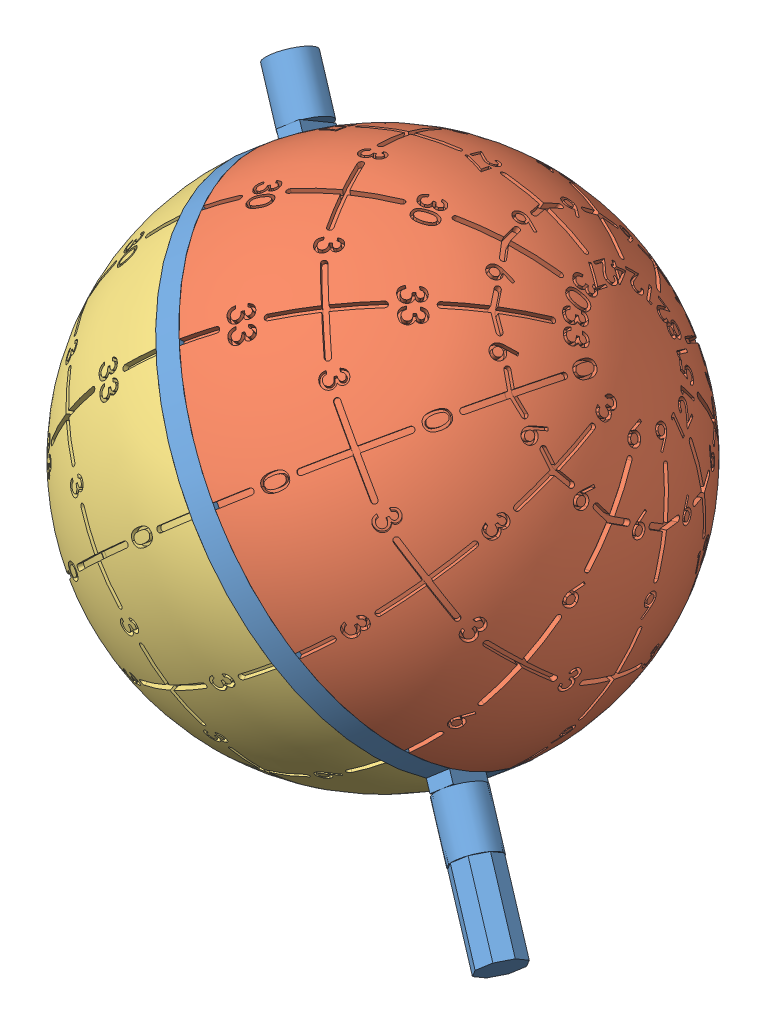
SolidWorks assembly plate, configuration Default. Lengths in mm.
Overall size (138.24 147.99 129.73).
8 component instances, 8 part files, 16 mates.
Components (placement in the parent):
- BallPlate-1: BallPlate [Default] x (0.678648 -0.634798 0.369415) z (0.007266 0.508751 0.860883) size (127.54 8 88.9)
- Ball_V9_final_Top-1: Ball_V9_final_Top [Default] x (0.658953 -0.734427 0.162472) z (0.162472 0.349875 0.9226) size (88.8 42.45 88.81)
- Ball_V9_final_Bot-1: Ball_V9_final_Bot [Default] x (0.658953 -0.734427 0.162472) z (0.162472 0.349875 0.9226) size (88.8 87.56 88.81)
- SKF 625-1: SKF 625 [Default] at (-1.8361 -1.4539 0.8747) x (0.734427 0.581553 -0.349875) z (0.162472 0.349875 0.9226) size (5 16 16)
- Servo-2: Servo [noHorn] at (1.3234 -9.0246 -17.9389) x (-0.007266 -0.508751 -0.860883) z (0.678648 -0.634798 0.369415) size (19.8 47.23 67)
- BallShaft-1: BallShaft [Default] at (1.6489 1.3057 -0.7855) x (-0.141735 -0.372726 -0.917053) z (0.663722 -0.723099 0.191314) size (13.5 16.75 13.5)
- YawServoGear-1: YawServoGear [Default] at (7.1858 7.691 -27.8667) x (0.658953 -0.734427 0.162472) z (-0.734427 -0.581553 0.349875) size (24.43 24.43 3)
- BallGear2-2: BallGear2 [Default] at (14.3213 11.3403 -6.8226) x (0.294586 0.191268 0.936288) z (-0.734427 -0.581553 0.349875) size (24.43 24.43 3)
Mates (geometry in assembly coordinates):
- Concentric1: concentric: circle of Ball_V9_final_Top-1; circle of BallPlate-1
- Coincident1: coincident: plane of BallPlate-1 through (1.4689 1.1631 -0.6998) normal (0.734427 0.581553 -0.349875); plane of Ball_V9_final_Top-1 through (1.4689 1.1631 -0.6998) normal (-0.734427 -0.581553 0.349875)
- Concentric2: concentric: circle of Ball_V9_final_Bot-1; circle of BallPlate-1
- Coincident2: coincident: plane of BallPlate-1 through (-1.4689 -1.1631 0.6998) normal (-0.734427 -0.581553 0.349875); plane of Ball_V9_final_Bot-1 through (-1.4689 -1.1631 0.6998) normal (0.734427 0.581553 -0.349875)
- Concentric3: concentric: circle of BallPlate-1; circle of SKF 625-1
- Coincident4: coincident: plane of BallPlate-1 through (1.8361 1.4539 -0.8747) normal (0.734427 0.581553 -0.349875); plane of SKF 625-1 through (-2.546 6.3378 -1.9551) normal (0.734427 0.581553 -0.349875)
- Tangent1: tangent: cylinder of BallPlate-1 through (1.8361 1.4539 -0.8747) axis (-0.734427 -0.581553 0.349875) radius 10.125; plane of Servo-2 through (-12.3813 8.8984 -16.9153) normal (0.007266 0.508751 0.860883)
- Coincident5: coincident: plane of BallPlate-1 through (1.4689 1.1631 -0.6998) normal (0.734427 0.581553 -0.349875); plane of Servo-2 through (1.3234 -9.0246 -17.9389) normal (-0.734427 -0.581553 0.349875)
- Parallel1: parallel: line of BallPlate-1 through (32.963 -30.3583 13.016) axis (-0.678648 0.634798 -0.369415); line of Servo-2 through (20.592 -21.3697 -22.3059) axis (-0.678648 0.634798 -0.369415)
- Lock4: lock: unknown of BallPlate-1; unknown of Servo-2
- Coincident6: coincident: plane of Servo-2 through (7.1858 7.691 -27.8667) normal (0.734427 0.581553 -0.349875); plane of YawServoGear-1 through (7.1858 7.691 -27.8667) normal (0.734427 0.581553 -0.349875)
- Concentric5: concentric: circle of Servo-2; circle of YawServoGear-1
- Coincident8: coincident: plane of YawServoGear-1 through (7.1858 7.691 -27.8667) normal (0.734427 0.581553 -0.349875); plane of BallGear2-2 through (14.3213 11.3403 -6.8226) normal (0.734427 0.581553 -0.349875)
- Coincident12: coincident: plane of BallShaft-1 through (14.4143 7.9102 -3.7542) normal (0.734427 0.581553 -0.349875); plane of BallGear2-2 through (12.1181 9.5956 -5.7729) normal (-0.734427 -0.581553 0.349875)
- Parallel3: parallel: plane of SKF 625-1 through (-0.009 3.5103 -1.3296) normal (0.734427 0.581553 -0.349875); plane of BallShaft-1 through (3.485 2.7595 -1.6602) normal (-0.734427 -0.581553 0.349875)
- Concentric8: concentric: circle of BallPlate-1; circle of BallShaft-1
